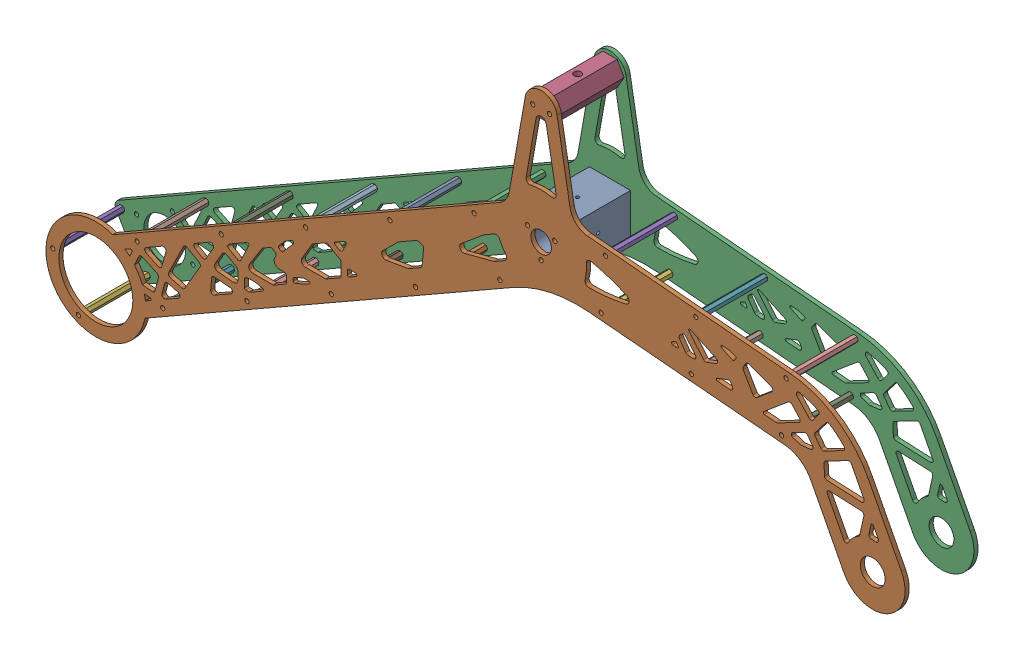
SolidWorks assembly Left Rocker Assy-2023, configuration Default. Lengths in mm.
Overall size (663.55 336.79 56.35).
22 component instances, 5 part files, 84 mates.
Components (placement in the parent):
- Rocker Adapter-2023-1: Rocker Adapter-2023 [Default] at origin size (31.75 31.75 50)
- Rocker Plate - Inner-2023-1: Rocker Plate - Inner-2023 [Default] at (0 0 25) size (663.55 336.79 3.17)
- Rocker Plate - Outer-2023-1: Rocker Plate - Outer-2023 [Default] at (0 0 -28.175) size (663.31 333.98 3.17)
- Differential Adapter-2023-1: Differential Adapter-2023 [Default] at (0 88.9125 0) size (21.94 19 50)
- Standoff Nut-2023-1: Standoff Nut-2023 [95947A502] at (-377.2333 -192.8465 -25) x (0 0 1) z (-1 0 0) size (50 4.5 5.2)
- Standoff Nut-2023-2: Standoff Nut-2023 [95947A502] at (-357.3649 -227.5632 -25) x (0 0 1) z (-0.987351 -0.158553 0) size (50 4.5 5.2)
- Standoff Nut-2023-3: Standoff Nut-2023 [95947A502] at (-292.2711 -190.3101 -25) x (0 0 1) z (-0.959125 -0.282984 0) size (50 4.5 5.2)
- Standoff Nut-2023-4: Standoff Nut-2023 [95947A502] at (-312.1394 -155.5934 -25) x (0 0 1) z (-0.928571 -0.371154 0) size (50 4.5 5.2)
- Standoff Nut-2023-5: Standoff Nut-2023 [95947A502] at (-247.0456 -118.3403 -25) x (0 0 1) z (-0.906989 -0.421154 0) size (50 4.5 5.2)
- Standoff Nut-2023-6: Standoff Nut-2023 [95947A502] at (-227.1773 -153.057 -25) x (0 0 1) z (-0.902849 -0.429957 0) size (50 4.5 5.2)
- Standoff Nut-2023-7: Standoff Nut-2023 [95947A502] at (-162.0835 -115.8038 -25) x (0 0 1) z (-0.919615 -0.39282 0) size (50 4.5 5.2)
- Standoff Nut-2023-8: Standoff Nut-2023 [95947A502] at (-181.9518 -81.0871 -25) x (0 0 1) z (-0.952324 -0.305088 0) size (50 4.5 5.2)
- Standoff Nut-2023-9: Standoff Nut-2023 [95947A502] at (-116.858 -43.834 -25) x (0 0 1) z (-0.985697 -0.168526 0) size (50 4.5 5.2)
- Standoff Nut-2023-10: Standoff Nut-2023 [95947A502] at (-96.9897 -78.5507 -25) x (0 0 1) z (-1 0 0) size (50 4.5 5.2)
- Standoff Nut-2023-11: Standoff Nut-2023 [95947A502] at (-51.7642 -6.5809 -25) x (0 0 1) z (-0.985697 0.168526 0) size (50 4.5 5.2)
- Standoff Nut-2023-12: Standoff Nut-2023 [95947A502] at (-31.8958 -41.2976 -25) x (0 0 1) z (-0.952324 0.305088 0) size (50 4.5 5.2)
- Standoff Nut-2023-13: Standoff Nut-2023 [95947A502] at (49.7555 15.7234 -25) x (0 0 1) z (-0.919615 0.39282 0) size (50 4.5 5.2)
- Standoff Nut-2023-14: Standoff Nut-2023 [95947A502] at (46.2693 -24.1244 -25) x (0 0 1) z (-0.902849 0.429957 0) size (50 4.5 5.2)
- Standoff Nut-2023-15: Standoff Nut-2023 [95947A502] at (119.4892 9.6224 -25) x (0 0 1) z (-0.906989 0.421154 0) size (50 4.5 5.2)
- Standoff Nut-2023-16: Standoff Nut-2023 [95947A502] at (116.0029 -30.2253 -25) x (0 0 1) z (-0.928571 0.371154 0) size (50 4.5 5.2)
- Standoff Nut-2023-17: Standoff Nut-2023 [95947A502] at (185.7366 -36.3262 -25) x (0 0 1) z (-0.959125 0.282984 0) size (50 4.5 5.2)
- Standoff Nut-2023-18: Standoff Nut-2023 [95947A502] at (189.2228 3.5215 -25) x (0 0 1) z (-0.987351 0.158553 0) size (50 4.5 5.2)
Mates (geometry in assembly coordinates):
- Concentric1: concentric anti-aligned: cylinder of Rocker Adapter-1 through (0 -12.1244 25) axis (0 0 -1) radius 1.25; cylinder of Rocker Plate - Inner-1 through (0 -12.1244 25) axis (0 0 1) radius 1.65
- Concentric2: concentric anti-aligned: cylinder of Rocker Adapter-1 through (10.5 6.0622 25) axis (0 0 -1) radius 1.25; cylinder of Rocker Plate - Inner-1 through (10.5 6.0622 25) axis (0 0 1) radius 1.65
- Coincident1: coincident anti-aligned: plane of Rocker Adapter-1 through (0 0 25) normal (0 0 1); plane of Rocker Plate - Inner-1 through (37.0941 36.9075 25) normal (0 0 -1)
- Concentric3: concentric anti-aligned: cylinder of Rocker Adapter-1 through (0 -12.1244 25) axis (0 0 -1) radius 1.25; cylinder of Rocker Plate - Outer-1 through (0 -12.1244 -28.175) axis (0 0 1) radius 1.65
- Concentric4: concentric anti-aligned: cylinder of Rocker Adapter-1 through (-10.5 6.0622 25) axis (0 0 -1) radius 1.25; cylinder of Rocker Plate - Outer-1 through (-10.5 6.0622 -28.175) axis (0 0 1) radius 1.65
- Coincident2: coincident anti-aligned: plane of Rocker Adapter-1 through (0 0 -25) normal (0 0 -1); plane of Rocker Plate - Outer-1 through (37.0941 36.9075 -25) normal (0 0 1)
- Concentric5: concentric aligned: cylinder of Rocker Plate - Outer-1 through (-6.5 88.9125 -25) axis (0 0 -1) radius 1.65; cylinder of Differential Adapter-1 through (-6.5 88.9125 25) axis (0 0 -1) radius 1.25
- Concentric6: concentric aligned: cylinder of Rocker Plate - Outer-1 through (6.5 88.9125 -25) axis (0 0 -1) radius 1.65; cylinder of Differential Adapter-1 through (6.5 88.9125 25) axis (0 0 -1) radius 1.25
- Concentric7: concentric aligned: cylinder of Rocker Plate - Inner-1 through (-6.5 88.9125 28.175) axis (0 0 -1) radius 1.65; cylinder of Differential Adapter-1 through (-6.5 88.9125 25) axis (0 0 -1) radius 1.25
- Concentric8: concentric aligned: cylinder of Rocker Plate - Inner-1 through (6.5 88.9125 28.175) axis (0 0 -1) radius 1.65; cylinder of Differential Adapter-1 through (6.5 88.9125 25) axis (0 0 -1) radius 1.25
- Coincident3: coincident anti-aligned: plane of Rocker Plate - Inner-1 through (37.0941 36.9075 25) normal (0 0 -1); plane of Differential Adapter-1 through (0 88.9125 25) normal (0 0 1)
- Coincident4: coincident anti-aligned: plane of Rocker Plate - Outer-1 through (37.0941 36.9075 -25) normal (0 0 1); plane of Differential Adapter-1 through (0 88.9125 -25) normal (0 0 -1)
- Concentric9: concentric anti-aligned: cylinder of Rocker Plate - Outer-1 through (-377.2333 -192.8465 -28.175) axis (0 0 1) radius 1.65; cylinder of Standoff Nut-1 through (-377.2333 -192.8465 -25) axis (0 0 -1) radius 1.5
- Concentric10: concentric anti-aligned: cylinder of Rocker Plate - Inner-1 through (-377.2333 -192.8465 25) axis (0 0 1) radius 1.65; cylinder of Standoff Nut-1 through (-377.2333 -192.8465 -25) axis (0 0 -1) radius 1.5
- Coincident5: coincident anti-aligned: plane of Rocker Plate - Inner-1 through (37.0941 36.9075 25) normal (0 0 -1); plane of Standoff Nut-1 through (-377.2333 -192.8465 25) normal (0 0 1)
- Coincident6: coincident anti-aligned: plane of Rocker Plate - Outer-1 through (37.0941 36.9075 -25) normal (0 0 1); plane of Standoff Nut-1 through (-377.2333 -192.8465 -25) normal (0 0 -1)
- Coincident7: coincident anti-aligned: plane of Rocker Plate - Inner-1 through (37.0941 36.9075 25) normal (0 0 -1); plane of Standoff Nut-2 through (-357.3649 -227.5632 25) normal (0 0 1)
- Coincident8: coincident anti-aligned: plane of Rocker Plate - Outer-1 through (37.0941 36.9075 -25) normal (0 0 1); plane of Standoff Nut-2 through (-357.3649 -227.5632 -25) normal (0 0 -1)
- Concentric11: concentric anti-aligned: cylinder of Rocker Plate - Outer-1 through (-357.3649 -227.5632 -28.175) axis (0 0 1) radius 1.65; cylinder of Standoff Nut-2 through (-357.3649 -227.5632 -25) axis (0 0 -1) radius 1.5
- Concentric12: concentric anti-aligned: cylinder of Rocker Plate - Inner-1 through (-357.3649 -227.5632 25) axis (0 0 1) radius 1.65; cylinder of Standoff Nut-2 through (-357.3649 -227.5632 -25) axis (0 0 -1) radius 1.5
- Coincident9: coincident anti-aligned: plane of Rocker Plate - Inner-1 through (37.0941 36.9075 25) normal (0 0 -1); plane of Standoff Nut-3 through (-292.2711 -190.3101 25) normal (0 0 1)
- Coincident10: coincident anti-aligned: plane of Rocker Plate - Outer-1 through (37.0941 36.9075 -25) normal (0 0 1); plane of Standoff Nut-3 through (-292.2711 -190.3101 -25) normal (0 0 -1)
- Concentric13: concentric anti-aligned: cylinder of Rocker Plate - Outer-1 through (-292.2711 -190.3101 -28.175) axis (0 0 1) radius 1.65; cylinder of Standoff Nut-3 through (-292.2711 -190.3101 -25) axis (0 0 -1) radius 1.5
- Concentric14: concentric anti-aligned: cylinder of Rocker Plate - Inner-1 through (-292.2711 -190.3101 25) axis (0 0 1) radius 1.65; cylinder of Standoff Nut-3 through (-292.2711 -190.3101 -25) axis (0 0 -1) radius 1.5
- Coincident11: coincident anti-aligned: plane of Rocker Plate - Inner-1 through (37.0941 36.9075 25) normal (0 0 -1); plane of Standoff Nut-4 through (-312.1394 -155.5934 25) normal (0 0 1)
- Coincident12: coincident anti-aligned: plane of Rocker Plate - Outer-1 through (37.0941 36.9075 -25) normal (0 0 1); plane of Standoff Nut-4 through (-312.1394 -155.5934 -25) normal (0 0 -1)
- Concentric15: concentric anti-aligned: cylinder of Rocker Plate - Outer-1 through (-312.1394 -155.5934 -28.175) axis (0 0 1) radius 1.65; cylinder of Standoff Nut-4 through (-312.1394 -155.5934 -25) axis (0 0 -1) radius 1.5
- Concentric16: concentric anti-aligned: cylinder of Rocker Plate - Inner-1 through (-312.1394 -155.5934 25) axis (0 0 1) radius 1.65; cylinder of Standoff Nut-4 through (-312.1394 -155.5934 -25) axis (0 0 -1) radius 1.5
- Coincident13: coincident anti-aligned: plane of Rocker Plate - Inner-1 through (37.0941 36.9075 25) normal (0 0 -1); plane of Standoff Nut-5 through (-247.0456 -118.3403 25) normal (0 0 1)
- Coincident14: coincident anti-aligned: plane of Rocker Plate - Outer-1 through (37.0941 36.9075 -25) normal (0 0 1); plane of Standoff Nut-5 through (-247.0456 -118.3403 -25) normal (0 0 -1)
- Concentric17: concentric anti-aligned: cylinder of Rocker Plate - Outer-1 through (-247.0456 -118.3403 -28.175) axis (0 0 1) radius 1.65; cylinder of Standoff Nut-5 through (-247.0456 -118.3403 -25) axis (0 0 -1) radius 1.5
- Concentric18: concentric anti-aligned: cylinder of Rocker Plate - Inner-1 through (-247.0456 -118.3403 25) axis (0 0 1) radius 1.65; cylinder of Standoff Nut-5 through (-247.0456 -118.3403 -25) axis (0 0 -1) radius 1.5
- Coincident15: coincident anti-aligned: plane of Rocker Plate - Inner-1 through (37.0941 36.9075 25) normal (0 0 -1); plane of Standoff Nut-6 through (-227.1773 -153.057 25) normal (0 0 1)
- Coincident16: coincident anti-aligned: plane of Rocker Plate - Outer-1 through (37.0941 36.9075 -25) normal (0 0 1); plane of Standoff Nut-6 through (-227.1773 -153.057 -25) normal (0 0 -1)
- Concentric19: concentric anti-aligned: cylinder of Rocker Plate - Outer-1 through (-227.1773 -153.057 -28.175) axis (0 0 1) radius 1.65; cylinder of Standoff Nut-6 through (-227.1773 -153.057 -25) axis (0 0 -1) radius 1.5
- Concentric20: concentric anti-aligned: cylinder of Rocker Plate - Inner-1 through (-227.1773 -153.057 25) axis (0 0 1) radius 1.65; cylinder of Standoff Nut-6 through (-227.1773 -153.057 -25) axis (0 0 -1) radius 1.5
- Coincident17: coincident anti-aligned: plane of Rocker Plate - Inner-1 through (37.0941 36.9075 25) normal (0 0 -1); plane of Standoff Nut-7 through (-162.0835 -115.8038 25) normal (0 0 1)
- Coincident18: coincident anti-aligned: plane of Rocker Plate - Outer-1 through (37.0941 36.9075 -25) normal (0 0 1); plane of Standoff Nut-7 through (-162.0835 -115.8038 -25) normal (0 0 -1)
- Concentric21: concentric anti-aligned: cylinder of Rocker Plate - Outer-1 through (-162.0835 -115.8038 -28.175) axis (0 0 1) radius 1.65; cylinder of Standoff Nut-7 through (-162.0835 -115.8038 -25) axis (0 0 -1) radius 1.5
- Concentric22: concentric anti-aligned: cylinder of Rocker Plate - Inner-1 through (-162.0835 -115.8038 25) axis (0 0 1) radius 1.65; cylinder of Standoff Nut-7 through (-162.0835 -115.8038 -25) axis (0 0 -1) radius 1.5
- Coincident19: coincident anti-aligned: plane of Rocker Plate - Inner-1 through (37.0941 36.9075 25) normal (0 0 -1); plane of Standoff Nut-8 through (-181.9518 -81.0871 25) normal (0 0 1)
- Coincident20: coincident anti-aligned: plane of Rocker Plate - Outer-1 through (37.0941 36.9075 -25) normal (0 0 1); plane of Standoff Nut-8 through (-181.9518 -81.0871 -25) normal (0 0 -1)
- Concentric23: concentric anti-aligned: cylinder of Rocker Plate - Outer-1 through (-181.9518 -81.0871 -28.175) axis (0 0 1) radius 1.65; cylinder of Standoff Nut-8 through (-181.9518 -81.0871 -25) axis (0 0 -1) radius 1.5
- Concentric24: concentric anti-aligned: cylinder of Rocker Plate - Inner-1 through (-181.9518 -81.0871 25) axis (0 0 1) radius 1.65; cylinder of Standoff Nut-8 through (-181.9518 -81.0871 -25) axis (0 0 -1) radius 1.5
- Coincident21: coincident anti-aligned: plane of Rocker Plate - Inner-1 through (37.0941 36.9075 25) normal (0 0 -1); plane of Standoff Nut-9 through (-116.858 -43.834 25) normal (0 0 1)
- Coincident22: coincident anti-aligned: plane of Rocker Plate - Outer-1 through (37.0941 36.9075 -25) normal (0 0 1); plane of Standoff Nut-9 through (-116.858 -43.834 -25) normal (0 0 -1)
- Concentric25: concentric anti-aligned: cylinder of Rocker Plate - Outer-1 through (-116.858 -43.834 -28.175) axis (0 0 1) radius 1.65; cylinder of Standoff Nut-9 through (-116.858 -43.834 -25) axis (0 0 -1) radius 1.5
- Concentric26: concentric anti-aligned: cylinder of Rocker Plate - Inner-1 through (-116.858 -43.834 25) axis (0 0 1) radius 1.65; cylinder of Standoff Nut-9 through (-116.858 -43.834 -25) axis (0 0 -1) radius 1.5
- Coincident23: coincident anti-aligned: plane of Rocker Plate - Inner-1 through (37.0941 36.9075 25) normal (0 0 -1); plane of Standoff Nut-10 through (-96.9897 -78.5507 25) normal (0 0 1)
- Coincident24: coincident anti-aligned: plane of Rocker Plate - Outer-1 through (37.0941 36.9075 -25) normal (0 0 1); plane of Standoff Nut-10 through (-96.9897 -78.5507 -25) normal (0 0 -1)
- Concentric27: concentric anti-aligned: cylinder of Rocker Plate - Outer-1 through (-96.9897 -78.5507 -28.175) axis (0 0 1) radius 1.65; cylinder of Standoff Nut-10 through (-96.9897 -78.5507 -25) axis (0 0 -1) radius 1.5
- Concentric28: concentric anti-aligned: cylinder of Rocker Plate - Inner-1 through (-96.9897 -78.5507 25) axis (0 0 1) radius 1.65; cylinder of Standoff Nut-10 through (-96.9897 -78.5507 -25) axis (0 0 -1) radius 1.5
- Coincident25: coincident anti-aligned: plane of Rocker Plate - Inner-1 through (37.0941 36.9075 25) normal (0 0 -1); plane of Standoff Nut-11 through (-51.7642 -6.5809 25) normal (0 0 1)
- Coincident26: coincident anti-aligned: plane of Rocker Plate - Outer-1 through (37.0941 36.9075 -25) normal (0 0 1); plane of Standoff Nut-11 through (-51.7642 -6.5809 -25) normal (0 0 -1)
- Concentric29: concentric anti-aligned: cylinder of Rocker Plate - Outer-1 through (-51.7642 -6.5809 -28.175) axis (0 0 1) radius 1.65; cylinder of Standoff Nut-11 through (-51.7642 -6.5809 -25) axis (0 0 -1) radius 1.5
- Concentric30: concentric anti-aligned: cylinder of Rocker Plate - Inner-1 through (-51.7642 -6.5809 25) axis (0 0 1) radius 1.65; cylinder of Standoff Nut-11 through (-51.7642 -6.5809 -25) axis (0 0 -1) radius 1.5
- Coincident27: coincident anti-aligned: plane of Rocker Plate - Inner-1 through (37.0941 36.9075 25) normal (0 0 -1); plane of Standoff Nut-12 through (-31.8958 -41.2976 25) normal (0 0 1)
- Coincident28: coincident anti-aligned: plane of Rocker Plate - Outer-1 through (37.0941 36.9075 -25) normal (0 0 1); plane of Standoff Nut-12 through (-31.8958 -41.2976 -25) normal (0 0 -1)
- Concentric31: concentric anti-aligned: cylinder of Rocker Plate - Outer-1 through (-31.8958 -41.2976 -28.175) axis (0 0 1) radius 1.65; cylinder of Standoff Nut-12 through (-31.8958 -41.2976 -25) axis (0 0 -1) radius 1.5
- Concentric32: concentric anti-aligned: cylinder of Rocker Plate - Inner-1 through (-31.8958 -41.2976 25) axis (0 0 1) radius 1.65; cylinder of Standoff Nut-12 through (-31.8958 -41.2976 -25) axis (0 0 -1) radius 1.5
- Coincident29: coincident anti-aligned: plane of Rocker Plate - Inner-1 through (37.0941 36.9075 25) normal (0 0 -1); plane of Standoff Nut-13 through (49.7555 15.7234 25) normal (0 0 1)
- Coincident30: coincident anti-aligned: plane of Rocker Plate - Outer-1 through (37.0941 36.9075 -25) normal (0 0 1); plane of Standoff Nut-13 through (49.7555 15.7234 -25) normal (0 0 -1)
- Concentric33: concentric anti-aligned: cylinder of Rocker Plate - Outer-1 through (49.7555 15.7234 -28.175) axis (0 0 1) radius 1.65; cylinder of Standoff Nut-13 through (49.7555 15.7234 -25) axis (0 0 -1) radius 1.5
- Concentric34: concentric anti-aligned: cylinder of Rocker Plate - Inner-1 through (49.7555 15.7234 25) axis (0 0 1) radius 1.65; cylinder of Standoff Nut-13 through (49.7555 15.7234 -25) axis (0 0 -1) radius 1.5
- Coincident31: coincident anti-aligned: plane of Rocker Plate - Inner-1 through (37.0941 36.9075 25) normal (0 0 -1); plane of Standoff Nut-14 through (46.2693 -24.1244 25) normal (0 0 1)
- Coincident32: coincident anti-aligned: plane of Rocker Plate - Outer-1 through (37.0941 36.9075 -25) normal (0 0 1); plane of Standoff Nut-14 through (46.2693 -24.1244 -25) normal (0 0 -1)
- Concentric35: concentric anti-aligned: cylinder of Rocker Plate - Outer-1 through (46.2693 -24.1244 -28.175) axis (0 0 1) radius 1.65; cylinder of Standoff Nut-14 through (46.2693 -24.1244 -25) axis (0 0 -1) radius 1.5
- Concentric36: concentric anti-aligned: cylinder of Rocker Plate - Inner-1 through (46.2693 -24.1244 25) axis (0 0 1) radius 1.65; cylinder of Standoff Nut-14 through (46.2693 -24.1244 -25) axis (0 0 -1) radius 1.5
- Coincident33: coincident anti-aligned: plane of Rocker Plate - Inner-1 through (37.0941 36.9075 25) normal (0 0 -1); plane of Standoff Nut-15 through (119.4892 9.6224 25) normal (0 0 1)
- Coincident34: coincident anti-aligned: plane of Rocker Plate - Outer-1 through (37.0941 36.9075 -25) normal (0 0 1); plane of Standoff Nut-15 through (119.4892 9.6224 -25) normal (0 0 -1)
- Concentric37: concentric anti-aligned: cylinder of Rocker Plate - Outer-1 through (119.4892 9.6224 -28.175) axis (0 0 1) radius 1.65; cylinder of Standoff Nut-15 through (119.4892 9.6224 -25) axis (0 0 -1) radius 1.5
- Concentric38: concentric anti-aligned: cylinder of Rocker Plate - Inner-1 through (119.4892 9.6224 25) axis (0 0 1) radius 1.65; cylinder of Standoff Nut-15 through (119.4892 9.6224 -25) axis (0 0 -1) radius 1.5
- Coincident35: coincident anti-aligned: plane of Rocker Plate - Inner-1 through (37.0941 36.9075 25) normal (0 0 -1); plane of Standoff Nut-16 through (116.0029 -30.2253 25) normal (0 0 1)
- Coincident36: coincident anti-aligned: plane of Rocker Plate - Outer-1 through (37.0941 36.9075 -25) normal (0 0 1); plane of Standoff Nut-16 through (116.0029 -30.2253 -25) normal (0 0 -1)
- Concentric39: concentric anti-aligned: cylinder of Rocker Plate - Outer-1 through (116.0029 -30.2253 -28.175) axis (0 0 1) radius 1.65; cylinder of Standoff Nut-16 through (116.0029 -30.2253 -25) axis (0 0 -1) radius 1.5
- Concentric40: concentric anti-aligned: cylinder of Rocker Plate - Inner-1 through (116.0029 -30.2253 25) axis (0 0 1) radius 1.65; cylinder of Standoff Nut-16 through (116.0029 -30.2253 -25) axis (0 0 -1) radius 1.5
- Coincident37: coincident anti-aligned: plane of Rocker Plate - Inner-1 through (37.0941 36.9075 25) normal (0 0 -1); plane of Standoff Nut-17 through (185.7366 -36.3262 25) normal (0 0 1)
- Coincident38: coincident anti-aligned: plane of Rocker Plate - Outer-1 through (37.0941 36.9075 -25) normal (0 0 1); plane of Standoff Nut-17 through (185.7366 -36.3262 -25) normal (0 0 -1)
- Concentric41: concentric anti-aligned: cylinder of Rocker Plate - Outer-1 through (185.7366 -36.3262 -28.175) axis (0 0 1) radius 1.65; cylinder of Standoff Nut-17 through (185.7366 -36.3262 -25) axis (0 0 -1) radius 1.5
- Concentric42: concentric anti-aligned: cylinder of Rocker Plate - Inner-1 through (185.7366 -36.3262 25) axis (0 0 1) radius 1.65; cylinder of Standoff Nut-17 through (185.7366 -36.3262 -25) axis (0 0 -1) radius 1.5
- Coincident39: coincident anti-aligned: plane of Rocker Plate - Inner-1 through (37.0941 36.9075 25) normal (0 0 -1); plane of Standoff Nut-18 through (189.2228 3.5215 25) normal (0 0 1)
- Coincident40: coincident anti-aligned: plane of Rocker Plate - Outer-1 through (37.0941 36.9075 -25) normal (0 0 1); plane of Standoff Nut-18 through (189.2228 3.5215 -25) normal (0 0 -1)
- Concentric43: concentric anti-aligned: cylinder of Rocker Plate - Outer-1 through (189.2228 3.5215 -28.175) axis (0 0 1) radius 1.65; cylinder of Standoff Nut-18 through (189.2228 3.5215 -25) axis (0 0 -1) radius 1.5
- Concentric44: concentric anti-aligned: cylinder of Rocker Plate - Inner-1 through (189.2228 3.5215 25) axis (0 0 1) radius 1.65; cylinder of Standoff Nut-18 through (189.2228 3.5215 -25) axis (0 0 -1) radius 1.5
